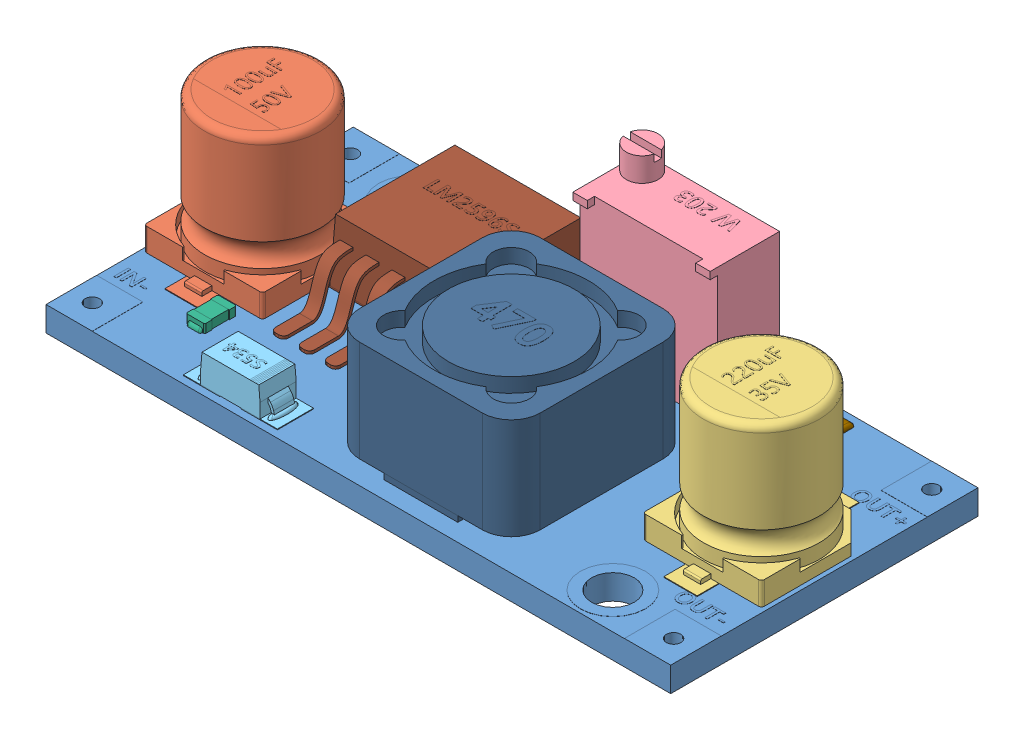
SolidWorks assembly converterLM2596, configuration Default. Lengths in mm.
Overall size (43.2 15.15 21.25).
12 component instances, 11 part files, 23 mates.
Components (placement in the parent):
- lm2596board-1: lm2596board [Default] at origin size (43.2 1.71 21.25)
- smd100uF-1: smd100uF [Default] at (-17.25 2.55 0) x (0 0 -1) z (1 0 0) size (11.2 9.76 8.2)
- smd220uF-2: smd220uF [Default] at (17.25 2.55 0) x (0 0 -1) z (1 0 0) size (11.2 9.76 8.2)
- TrimmerW203-1: TrimmerW203 [Default] at (4.6271 6.95 -9.1276) size (9.5 15.15 4.81)
- smdS537diode-1: smdS537diode [Default] at (-9.35 1.75 8.875) x (-1 0 0) z (0 0 -1) size (6.5 2.13 2.5)
- smdceramiccapacitor-1: smdceramiccapacitor [Default] at (-15 1.7 5.7969) x (0 0 1) z (-1 0 0) size (2.55 0.62 1.3)
- smdceramiccapacitor-2: smdceramiccapacitor [Default] at (-1.3196 1.7 -5.2916) x (0 0 1) z (-1 0 0) size (2.55 0.62 1.3)
- smdResistor331-1: smdResistor331 [Default] at (-1.2696 1.7 -8.4665) x (0 0 1) z (-1 0 0) size (2.54 0.62 1.34)
- smdResistor102-1: smdResistor102 [Default] at (10.7771 1.7 -8.4665) x (0 0 -1) z (1 0 0) size (2.54 0.62 1.34)
- smdLED-1: smdLED [Default] at (13.0521 1.75 -8.4701) x (0 0 -1) z (1 0 0) size (3.2 0.84 1.28)
- smbInductor470-1: smbInductor470 [Default] at (3.1271 2.1 3.175) size (12.5 7.41 12.5)
- LM2596S-1: LM2596S [Default] at (-8.0627 1.8 -4.5407) size (9.8 4.61 14.95)
Mates (geometry in assembly coordinates):
- Coincident2: coincident anti-aligned: plane of lm2596board-1 through (0 1.7 0) normal (0 1 0); plane of smd100uF-1 through (-17.25 1.7 0) normal (0 -1 0)
- Coincident3: coincident anti-aligned: plane of smd100uF-1 through (-17.25 2.55 0) normal (0 0 -1); plane of assembly through (0 0 0) normal (0 0 1)
- Distance1: distance = 0.25 mm aligned: plane of smd100uF-1 through (-21.35 1.75 -4.1) normal (-1 0 0); plane of lm2596board-1 through (-21.6 1.7 10.625) normal (-1 0 0)
- Coincident5: coincident aligned: plane of smd100uF-1 through (-21.35 1.75 4.1) normal (0 0 1); plane of smd220uF-2 through (13.15 1.75 4.1) normal (0 0 1)
- Coincident6: coincident anti-aligned: plane of lm2596board-1 through (0 1.7 0) normal (0 1 0); plane of smd220uF-2 through (17.25 1.7 0) normal (0 -1 0)
- Distance2: distance = 0.25 mm aligned: plane of smd220uF-2 through (21.35 1.75 -4.1) normal (1 0 0); plane of lm2596board-1 through (21.6 1.7 10.625) normal (1 0 0)
- Coincident8: coincident anti-aligned: plane of lm2596board-1 through (0 1.7 0) normal (0 1 0); plane of TrimmerW203-1 through (-0.1229 1.7 -4.8276) normal (0 -1 0)
- Coincident9: coincident anti-aligned: plane of lm2596board-1 through (0 1.7 0) normal (0 1 0); plane of smdS537diode-1 through (-9.35 1.7 8.875) normal (0 -1 0)
- Distance3: distance = 0.5 mm aligned: plane of smdS537diode-1 through (-7.3 3.75 10.125) normal (0 0 1); plane of lm2596board-1 through (-21.6 1.7 10.625) normal (0 0 1)
- Distance4: distance = 10.2 mm aligned: plane of smdS537diode-1 through (-11.4 3.75 7.625) normal (-1 0 0); plane of lm2596board-1 through (-21.6 1.7 10.625) normal (-1 0 0)
- Coincident12: coincident anti-aligned: plane of lm2596board-1 through (0 1.7 0) normal (0 1 0); plane of smdceramiccapacitor-1 through (-15 1.7 5.7969) normal (0 -1 0)
- Distance5: distance = 6 mm aligned: plane of smdceramiccapacitor-1 through (-15.6 3.9971 5.1969) normal (-1 0 0); plane of lm2596board-1 through (-21.6 1.7 10.625) normal (-1 0 0)
- Coincident14: coincident anti-aligned: plane of lm2596board-1 through (0 1.7 0) normal (0 1 0); plane of smdResistor331-1 through (-1.2696 1.7 -8.4665) normal (0 -1 0)
- Coincident16: coincident aligned: plane of smdceramiccapacitor-2 through (-1.9196 3.9971 -5.8916) normal (-1 0 0); plane of smdResistor331-1 through (-1.9196 2.3 -9.5665) normal (-1 0 0)
- Coincident17: coincident anti-aligned: plane of lm2596board-1 through (0 1.7 0) normal (0 1 0); plane of smdResistor102-1 through (10.7771 1.7 -8.4665) normal (0 -1 0)
- Distance6: distance = 0.75 mm anti-aligned: plane of smdResistor102-1 through (10.1271 2.3 -7.3665) normal (-1 0 0); plane of TrimmerW203-1 through (9.3771 2.2 -4.8276) normal (1 0 0)
- Coincident19: coincident aligned: plane of smdResistor331-1 through (-1.9196 2.3 -9.5665) normal (0 0 -1); plane of smdResistor102-1 through (11.4271 2.3 -9.5665) normal (0 0 -1)
- Coincident20: coincident anti-aligned: plane of lm2596board-1 through (0 1.7 0) normal (0 1 0); plane of smdLED-1 through (13.0521 1.7 -8.4701) normal (0 -1 0)
- Distance7: distance = 1 mm anti-aligned: plane of smdLED-1 through (12.4271 2.5 -7.8451) normal (-1 0 0); plane of smdResistor102-1 through (11.4271 2.3 -7.3665) normal (1 0 0)
- Coincident22: coincident anti-aligned: plane of lm2596board-1 through (0 1.7 0) normal (0 1 0); plane of smbInductor470-1 through (3.1271 1.7 3.175) normal (0 -1 0)
- Coincident24: coincident aligned: plane of TrimmerW203-1 through (9.3771 2.2 -4.8276) normal (1 0 0); plane of smbInductor470-1 through (9.3771 9.1 9.425) normal (1 0 0)
- Distance8: distance = 1.2 mm aligned: plane of smbInductor470-1 through (-3.1229 9.1 9.425) normal (0 0 1); plane of lm2596board-1 through (-21.6 1.7 10.625) normal (0 0 1)
- Coincident26: coincident anti-aligned: plane of lm2596board-1 through (0 1.7 0) normal (0 1 0); plane of LM2596S-1 through (-8.0627 1.7 -4.5407) normal (0 -1 0)
